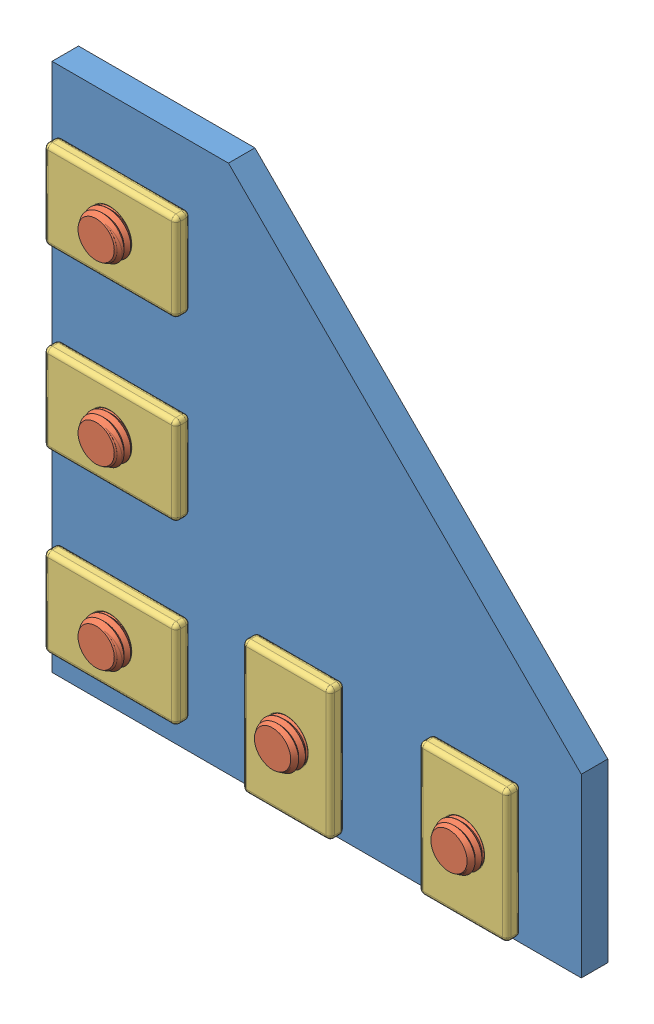
SolidWorks assembly 5 Hole 90 Degree Bracket with Bolts - Left Hand, configuration Default. Lengths in mm.
Overall size (60 60 10.1).
16 component instances, 3 part files, 15 mates.
Components (placement in the parent):
- 5 Hole 90 Degree Joining Plate-1: 5 Hole 90 Degree Joining Plate [Default] at (4.3285 16.0061 65.9875) size (60 60 3)
- 5mm x 8mm Bolt with Tee Nut-1: 5mm x 8mm Bolt with Tee Nut [Default] at (24.8053 58.2866 96.0812) x (0 0 1) z (-1 0 0) size (10.1 10 15)
  - 5mm x 8mm Low Profile Socket Head Screw-1: 5mm x 8mm Low Profile Socket Head Screw [5mm x 8mm Low Profile] at (-34.8438 7.7195 10.4769) size (10.1 9.5 9.5)
  - Tee nut-1: Tee nut [Default] at (-28.2938 2.7205 17.9769) x (0 0 -1) z (1 0 0) size (15 10 3.3)
- 5mm x 8mm Bolt with Tee Nut-2: 5mm x 8mm Bolt with Tee Nut [Default] at (24.8053 38.2866 96.0812) x (0 0 1) z (-1 0 0) size (10.1 10 15)
  - 5mm x 8mm Low Profile Socket Head Screw-1: 5mm x 8mm Low Profile Socket Head Screw [5mm x 8mm Low Profile] at (-34.8438 7.7195 10.4769) size (10.1 9.5 9.5)
  - Tee nut-1: Tee nut [Default] at (-28.2938 2.7205 17.9769) x (0 0 -1) z (1 0 0) size (15 10 3.3)
- 5mm x 8mm Bolt with Tee Nut-3: 5mm x 8mm Bolt with Tee Nut [Default] at (24.8053 18.2866 96.0812) x (0 0 1) z (-1 0 0) size (10.1 10 15)
  - 5mm x 8mm Low Profile Socket Head Screw-1: 5mm x 8mm Low Profile Socket Head Screw [5mm x 8mm Low Profile] at (-34.8438 7.7195 10.4769) size (10.1 9.5 9.5)
  - Tee nut-1: Tee nut [Default] at (-28.2938 2.7205 17.9769) x (0 0 -1) z (1 0 0) size (15 10 3.3)
- 5mm x 8mm Bolt with Tee Nut-4: 5mm x 8mm Bolt with Tee Nut [Default] at (26.609 15.5292 96.0812) x (0 0 1) z (0 1 0) size (10.1 10 15)
  - 5mm x 8mm Low Profile Socket Head Screw-1: 5mm x 8mm Low Profile Socket Head Screw [5mm x 8mm Low Profile] at (-34.8438 7.7195 10.4769) size (10.1 9.5 9.5)
  - Tee nut-1: Tee nut [Default] at (-28.2938 2.7205 17.9769) x (0 0 -1) z (1 0 0) size (15 10 3.3)
- 5mm x 8mm Bolt with Tee Nut-5: 5mm x 8mm Bolt with Tee Nut [Default] at (46.609 15.5292 96.0812) x (0 0 1) z (0 1 0) size (10.1 10 15)
  - 5mm x 8mm Low Profile Socket Head Screw-1: 5mm x 8mm Low Profile Socket Head Screw [5mm x 8mm Low Profile] at (-34.8438 7.7195 10.4769) size (10.1 9.5 9.5)
  - Tee nut-1: Tee nut [Default] at (-28.2938 2.7205 17.9769) x (0 0 -1) z (1 0 0) size (15 10 3.3)
Mates (geometry in assembly coordinates):
- Coincident11: coincident anti-aligned: plane of 5 Hole 90 Degree Joining Plate-1 through (4.3285 16.0061 62.9875) normal (0 0 -1); plane of 5mm x 8mm Bolt with Tee Nut-5/5mm x 8mm Low Profile Socket Head Screw-1 through (56.8285 26.0061 62.9875) normal (0 0 1)
- Coincident12: coincident anti-aligned: plane of 5 Hole 90 Degree Joining Plate-1 through (4.3285 16.0061 62.9875) normal (0 0 -1); plane of 5mm x 8mm Bolt with Tee Nut-4/5mm x 8mm Low Profile Socket Head Screw-1 through (36.8285 26.0061 62.9875) normal (0 0 1)
- Coincident13: coincident anti-aligned: plane of 5 Hole 90 Degree Joining Plate-1 through (4.3285 16.0061 62.9875) normal (0 0 -1); plane of 5mm x 8mm Bolt with Tee Nut-3/5mm x 8mm Low Profile Socket Head Screw-1 through (14.3285 28.5061 62.9875) normal (0 0 1)
- Coincident14: coincident anti-aligned: plane of 5 Hole 90 Degree Joining Plate-1 through (4.3285 16.0061 62.9875) normal (0 0 -1); plane of 5mm x 8mm Bolt with Tee Nut-2/5mm x 8mm Low Profile Socket Head Screw-1 through (14.3285 48.5061 62.9875) normal (0 0 1)
- Coincident15: coincident anti-aligned: plane of 5 Hole 90 Degree Joining Plate-1 through (4.3285 16.0061 62.9875) normal (0 0 -1); plane of 5mm x 8mm Bolt with Tee Nut-1/5mm x 8mm Low Profile Socket Head Screw-1 through (14.3285 68.5061 62.9875) normal (0 0 1)
- Concentric6: concentric anti-aligned: cylinder of 5 Hole 90 Degree Joining Plate-1 through (54.3285 26.0061 62.9875) axis (0 0 1) radius 2.5; circle of 5mm x 8mm Bolt with Tee Nut-5/Tee nut-1
- Concentric7: concentric aligned: cylinder of 5 Hole 90 Degree Joining Plate-1 through (34.3285 26.0061 62.9875) axis (0 0 1) radius 2.5; cylinder of 5mm x 8mm Bolt with Tee Nut-4/Tee nut-1 through (34.3285 26.0061 66.1375) axis (0 0 1) radius 2.6
- Concentric8: concentric aligned: cylinder of 5 Hole 90 Degree Joining Plate-1 through (14.3285 26.0061 62.9875) axis (0 0 1) radius 2.5; cylinder of 5mm x 8mm Bolt with Tee Nut-3/Tee nut-1 through (14.3285 26.0061 66.1375) axis (0 0 1) radius 2.6
- Concentric9: concentric aligned: cylinder of 5 Hole 90 Degree Joining Plate-1 through (14.3285 46.0061 62.9875) axis (0 0 1) radius 2.5; cylinder of 5mm x 8mm Bolt with Tee Nut-2/Tee nut-1 through (14.3285 46.0061 66.1375) axis (0 0 1) radius 2.6
- Concentric10: concentric aligned: cylinder of 5 Hole 90 Degree Joining Plate-1 through (14.3285 66.0061 62.9875) axis (0 0 1) radius 2.5; cylinder of 5mm x 8mm Bolt with Tee Nut-1/Tee nut-1 through (14.3285 66.0061 66.1375) axis (0 0 1) radius 2.6
- Parallel4: parallel aligned: plane of 5 Hole 90 Degree Joining Plate-1 through (4.3285 16.0061 62.9875) normal (-1 0 0); plane of 5mm x 8mm Bolt with Tee Nut-1/Tee nut-1 through (6.8285 61.0071 69.4375) normal (-1 0 0)
- Parallel5: parallel aligned: plane of 5 Hole 90 Degree Joining Plate-1 through (4.3285 16.0061 62.9875) normal (-1 0 0); plane of 5mm x 8mm Bolt with Tee Nut-2/Tee nut-1 through (6.8285 41.0071 69.4375) normal (-1 0 0)
- Parallel6: parallel aligned: plane of 5 Hole 90 Degree Joining Plate-1 through (4.3285 16.0061 62.9875) normal (-1 0 0); plane of 5mm x 8mm Bolt with Tee Nut-3/Tee nut-1 through (6.8285 21.0071 69.4375) normal (-1 0 0)
- Parallel7: parallel aligned: plane of 5 Hole 90 Degree Joining Plate-1 through (4.3285 16.0061 62.9875) normal (0 -1 0); plane of 5mm x 8mm Bolt with Tee Nut-4/Tee nut-1 through (29.3295 18.5061 69.4375) normal (0 -1 0)
- Parallel8: parallel aligned: plane of 5 Hole 90 Degree Joining Plate-1 through (4.3285 16.0061 62.9875) normal (0 -1 0); plane of 5mm x 8mm Bolt with Tee Nut-5/Tee nut-1 through (49.3295 18.5061 69.4375) normal (0 -1 0)
